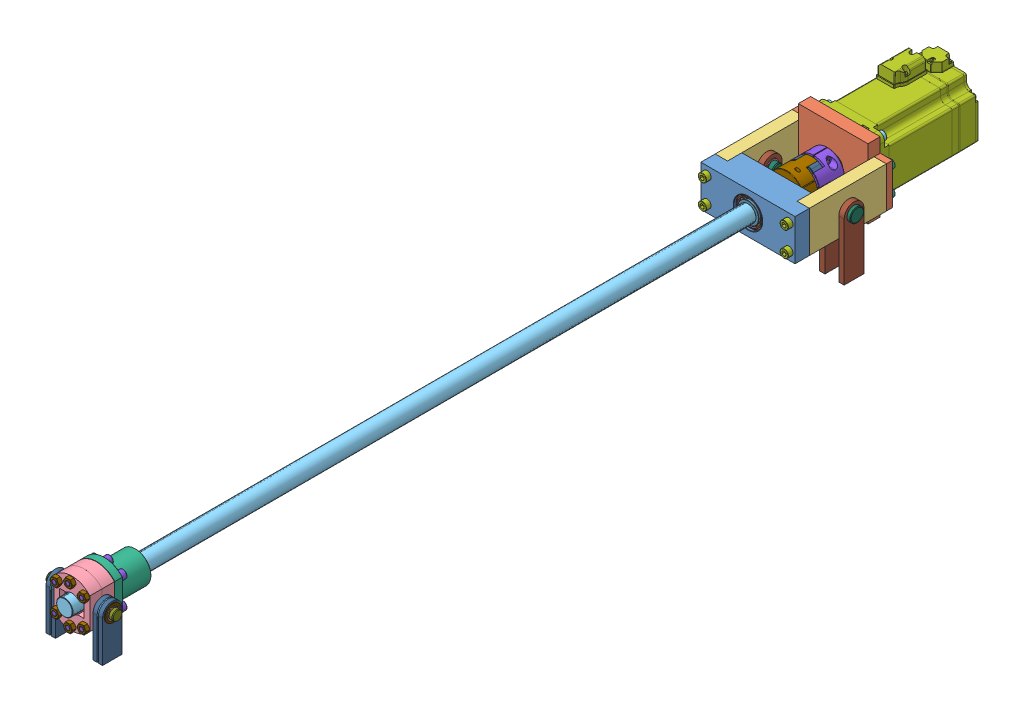
SolidWorks assembly full_assembly, configuration Domyślna. Lengths in mm.
Overall size (138 126.5 1076.27).
102 component instances, 29 part files, 150 mates.
Components (placement in the parent):
- kołyska gora-1: kołyska gora [Domyślna] at (65 70 76.5) x (-1 0 0) z (0 0 -1) size (115 50 35)
- kolyska doł-1: kolyska doł [Domyślna] at (65 70 -42.5) size (115 85 15)
- kolyska bok-2: kolyska bok [Domyślna] at (22.5 45 -35) x (0 1 0) z (0 0 1) size (50 15 94)
- kolyska bok-1: kolyska bok [Domyślna] at (122.5 45 -35) x (0 1 0) z (0 0 1) size (50 15 94)
- nakladka-1: nakladka [Domyślna] at (65 70 902.2231) x (0 -1 0) z (0 0 -1) size (58 44 15)
- nakladka-2: nakladka [Domyślna] at (65 70 872.2231) x (0 1 0) z (0 0 1) size (58 44 15)
- sruba-1: sruba [Domyślna] at (65 70 911.25) x (0 -1 0) z (0 0 -1) size (20 20 900)
- kolnierz-1: kolnierz [Domyślna] at (65 70 862.2231) x (0 1 0) z (0 0 1) size (58 44 48)
- serwo hiwin-1: serwo hiwin [Domyślna] at (64.9998 69.9998 -39.5) x (1 0 0) z (0 1 0) size (80.01 162.52 96.51)
- sprzeglo ekl 19 12-2: sprzeglo ekl 19 12 [Domyślna] at (55.554 -10.7595 3.0501) x (-1 0 0) z (0 1 0) size (83.78 50.01 62.16)
  - EKL_Size20.STEP-1: EKL_Size20.STEP [Domyślna] at (-9.446 -23.7001 80.7595) size (83.78 50.01 62.16)
    - 3D_EKL_020_Nabe1.STEP-1: 3D_EKL_020_Nabe1.STEP [Domyślna] at origin size (83.78 31.01 42)
    - 3D_EKL_020_Nabe2.STEP-1: 3D_EKL_020_Nabe2.STEP [Domyślna] x (0.218377 0 -0.975864) z (0.975864 0 0.218377) size (51.25 31.01 42.01)
    - 3D_EKL_020_Stern.STEP-1: 3D_EKL_020_Stern.STEP [Domyślna] x (0.866025 0 0.5) z (-0.5 0 0.866025) size (39.47 12 42)
- SKF_30202-1: SKF_30202 [Default] at (65 70 64.5) x (0 0 1) z (0.198521 -0.980097 0) size (12.37 35 35)
  - SKF_30202_3-1: SKF_30202_3 [Default] x (1 0 0) z (0 0 -1) size (9.25 35 35)
  - SKF_30202_5-1: SKF_30202_5 [Default] x (1 0 0) z (0 -0.433884 -0.900969) size (8.32 5.94 4.84)
  - SKF_30202_5-2: SKF_30202_5 [Default] x (1 0 0) z (0 -0.781831 -0.62349) size (8.32 5.94 4.84)
  - SKF_30202_5-3: SKF_30202_5 [Default] x (1 0 0) z (0 -0.974928 -0.222521) size (8.32 5.94 4.84)
  - SKF_30202_5-4: SKF_30202_5 [Default] x (1 0 0) z (0 -0.974928 0.222521) size (8.32 5.94 4.84)
  - SKF_30202_5-5: SKF_30202_5 [Default] x (1 0 0) z (0 -0.781831 0.62349) size (8.32 5.94 4.84)
  - SKF_30202_5-6: SKF_30202_5 [Default] x (1 0 0) z (0 -0.433884 0.900969) size (8.32 5.94 4.84)
  - SKF_30202_5-7: SKF_30202_5 [Default] at origin size (8.32 5.94 4.84)
  - SKF_30202_5-8: SKF_30202_5 [Default] x (1 0 0) z (0 0.433884 0.900969) size (8.32 5.94 4.84)
  - SKF_30202_5-9: SKF_30202_5 [Default] x (1 0 0) z (0 0.781831 0.62349) size (8.32 5.94 4.84)
  - SKF_30202_5-10: SKF_30202_5 [Default] x (1 0 0) z (0 0.974928 0.222521) size (8.32 5.94 4.84)
  - SKF_30202_5-11: SKF_30202_5 [Default] x (1 0 0) z (0 0.974928 -0.222521) size (8.32 5.94 4.84)
  - SKF_30202_5-12: SKF_30202_5 [Default] x (1 0 0) z (0 0.781831 -0.62349) size (8.32 5.94 4.84)
  - SKF_30202_5-13: SKF_30202_5 [Default] x (1 0 0) z (0 0.433884 -0.900969) size (8.32 5.94 4.84)
  - SKF_30202_5-14: SKF_30202_5 [Default] x (1 0 0) z (0 0 -1) size (8.32 5.94 4.84)
  - SKF_30202_20-1: SKF_30202_20 [Default] x (1 0 0) z (0 0 -1) size (11.52 31.49 31.49)
  - SKF_30202_22-1: SKF_30202_22 [Default] x (1 0 0) z (0 0 -1) size (11 25.6 25.6)
- SKF_30202-2: SKF_30202 [Default] at (65 70 53.5) x (0 0 -1) z (-0.411353 -0.911476 0) size (12.37 35 35)
  - SKF_30202_3-1: SKF_30202_3 [Default] x (1 0 0) z (0 0 -1) size (9.25 35 35)
  - SKF_30202_5-1: SKF_30202_5 [Default] x (1 0 0) z (0 -0.433884 -0.900969) size (8.32 5.94 4.84)
  - SKF_30202_5-2: SKF_30202_5 [Default] x (1 0 0) z (0 -0.781831 -0.62349) size (8.32 5.94 4.84)
  - SKF_30202_5-3: SKF_30202_5 [Default] x (1 0 0) z (0 -0.974928 -0.222521) size (8.32 5.94 4.84)
  - SKF_30202_5-4: SKF_30202_5 [Default] x (1 0 0) z (0 -0.974928 0.222521) size (8.32 5.94 4.84)
  - SKF_30202_5-5: SKF_30202_5 [Default] x (1 0 0) z (0 -0.781831 0.62349) size (8.32 5.94 4.84)
  - SKF_30202_5-6: SKF_30202_5 [Default] x (1 0 0) z (0 -0.433884 0.900969) size (8.32 5.94 4.84)
  - SKF_30202_5-7: SKF_30202_5 [Default] at origin size (8.32 5.94 4.84)
  - SKF_30202_5-8: SKF_30202_5 [Default] x (1 0 0) z (0 0.433884 0.900969) size (8.32 5.94 4.84)
  - SKF_30202_5-9: SKF_30202_5 [Default] x (1 0 0) z (0 0.781831 0.62349) size (8.32 5.94 4.84)
  - SKF_30202_5-10: SKF_30202_5 [Default] x (1 0 0) z (0 0.974928 0.222521) size (8.32 5.94 4.84)
  - SKF_30202_5-11: SKF_30202_5 [Default] x (1 0 0) z (0 0.974928 -0.222521) size (8.32 5.94 4.84)
  - SKF_30202_5-12: SKF_30202_5 [Default] x (1 0 0) z (0 0.781831 -0.62349) size (8.32 5.94 4.84)
  - SKF_30202_5-13: SKF_30202_5 [Default] x (1 0 0) z (0 0.433884 -0.900969) size (8.32 5.94 4.84)
  - SKF_30202_5-14: SKF_30202_5 [Default] x (1 0 0) z (0 0 -1) size (8.32 5.94 4.84)
  - SKF_30202_20-1: SKF_30202_20 [Default] x (1 0 0) z (0 0 -1) size (11.52 31.49 31.49)
  - SKF_30202_22-1: SKF_30202_22 [Default] x (1 0 0) z (0 0 -1) size (11 25.6 25.6)
- sworzen 12x30-1: sworzen 12x30 [Domyślna] at (-4 70 12) x (1 0 0) z (0 -1 0) size (41 17 17)
- sworzen 12x30-2: sworzen 12x30 [Domyślna] at (134 70 12) x (-1 0 0) z (0 1 0) size (41 17 17)
- sworzen krótki-3: sworzen krótki [Domyślna] at (76 70 887.2231) size (30 17 17)
- sworzen krótki-4: sworzen krótki [Domyślna] at (53.9821 70 887.2231) x (-1 0 0) z (0 0 1) size (30 17 17)
- tuleja slizgowa-1: tuleja slizgowa [Domyślna] at (6.5 70 12) x (1 0 0) z (0 0.085752 0.996317) size (7 20 20)
- tuleja slizgowa-2: tuleja slizgowa [Domyślna] at (106.5 70 12) size (7 20 20)
- tuleja slizgowa-3: tuleja slizgowa [Domyślna] at (123.5 70 12) x (-1 0 0) z (0 -0.010008 -0.99995) size (7 20 20)
- tuleja slizgowa-4: tuleja slizgowa [Domyślna] at (23.5 70 12) x (-1 0 0) z (0 0 -1) size (7 20 20)
- tuleja krotka-11: tuleja krotka [Domyślna] at (87 70 887.2231) size (6 20 20)
- tuleja krotka-12: tuleja krotka [Domyślna] at (29.4821 70 887.2231) x (1 0 0) z (0 0.988972 -0.148103) size (6 20 20)
- tuleja krotka-13: tuleja krotka [Domyślna] at (43 70 887.2231) x (-1 0 0) z (0 0 -1) size (6 20 20)
- tuleja krotka-14: tuleja krotka [Domyślna] at (100.5 70 887.2231) x (-1 0 0) z (0 0 -1) size (6 20 20)
- podkladka slizgowa-3: podkladka slizgowa [Domyślna] at (35.5 70 887.2231) x (0 0 -1) z (1 0 0) size (24 24 1.5)
- podkladka slizgowa-4: podkladka slizgowa [Domyślna] at (93 70 887.2231) x (0 0 -1) z (1 0 0) size (24 24 1.5)
- kn 02 din 981-1: kn 02 din 981 [Default] at (65 70 40.75) x (0 0 -1) z (-0.707107 0.707107 0) size (5 22 22)
- podkladka lozysko-1: podkladka lozysko [Default] at (65 70 40.75) x (0 -1 0) z (0 0 1) size (28 27.86 1)
- seger-1: seger [Default] at (99 70 12) x (0 0 -1) z (1 0 0) size (14.2 16.59 1)
- seger-2: seger [Default] at (30 70 12) x (0 0 -1) z (1 0 0) size (14.2 16.59 1)
- seger-6: seger [Default] at (28.4821 70 887.2231) x (0 1 0) z (1 0 0) size (14.2 16.59 1)
- seger-7: seger [Default] at (100.5 70 887.2231) x (0 1 0) z (1 0 0) size (14.2 16.59 1)
- m6 16mm-1: m6 16mm [Default] at (96.8198 38.1798 -50.5) x (0.495459 -0.868632 0) z (0 0 -1) size (10 10 22)
- m6 16mm-2: m6 16mm [Default] at (33.1798 38.1798 -50.5) x (-0.495459 0.868632 0) z (0 0 -1) size (10 10 22)
- m6 16mm-3: m6 16mm [Default] at (33.1798 101.8198 -50.5) x (-1 0 0) z (0 0 -1) size (10 10 22)
- m6 16mm-4: m6 16mm [Default] at (96.8198 101.8198 -50.5) x (-0.999986 0.005236 0) z (0 0 -1) size (10 10 22)
- m6 20mm-1: m6 20mm [Default] at (115 85 -42.5) x (-1 0 0) z (0 0 -1) size (10 10 26)
- m6 20mm-2: m6 20mm [Default] at (115 55 -42.5) x (-1 0 0) z (0 0 -1) size (10 10 26)
- m6 20mm-3: m6 20mm [Default] at (15 85 -42.5) x (-1 0 0) z (0 0 -1) size (10 10 26)
- m6 20mm-4: m6 20mm [Default] at (15 55 -42.5) x (-1 0 0) z (0 0 -1) size (10 10 26)
- m6 30mm-1: m6 30mm [Default] at (115 55 76.5) size (10 10 36)
- m6 30mm-2: m6 30mm [Default] at (15 55 76.5) size (10 10 36)
- m6 30mm-3: m6 30mm [Default] at (115 85 76.5) size (10 10 36)
- m6 30mm-4: m6 30mm [Default] at (15 85 76.5) size (10 10 36)
- m6 45mm-1: m6 45mm [Default] at (81.617 86.617 862.2231) x (-0.923728 -0.383049 0) z (0 0 -1) size (10 10 51)
- m6 45mm-2: m6 45mm [Default] at (65 93.5 862.2231) x (-0.923728 -0.383049 0) z (0 0 -1) size (10 10 51)
- m6 45mm-3: m6 45mm [Default] at (81.617 53.383 862.2231) x (-0.923728 -0.383049 0) z (0 0 -1) size (10 10 51)
- m6 45mm-4: m6 45mm [Default] at (48.383 86.617 862.2231) x (-0.923728 -0.383049 0) z (0 0 -1) size (10 10 51)
- m6 45mm-5: m6 45mm [Default] at (65 46.5 862.2231) x (-0.923728 -0.383049 0) z (0 0 -1) size (10 10 51)
- m6 45mm-6: m6 45mm [Default] at (48.383 53.383 862.2231) x (-0.923728 -0.383049 0) z (0 0 -1) size (10 10 51)
- nakretka m6-1: nakretka m6 [Default] at (48.383 53.383 902.2231) size (11.55 10 5.26)
- nakretka m6-2: nakretka m6 [Default] at (65 46.5 902.2231) size (11.55 10 5.26)
- nakretka m6-3: nakretka m6 [Default] at (81.617 53.383 902.2231) size (11.55 10 5.26)
- nakretka m6-4: nakretka m6 [Default] at (65 93.5 902.2231) size (11.55 10 5.26)
- nakretka m6-5: nakretka m6 [Default] at (48.383 86.617 902.2231) size (11.55 10 5.26)
- nakretka m6-6: nakretka m6 [Default] at (81.617 86.617 902.2231) size (11.55 10 5.26)
- ciegno-9: ciegno [Domyślna] at (42 70 875.2231) x (0 -1 0) z (-1 0 0) size (62 24 5)
- ciegno-10: ciegno [Domyślna] at (88 70 899.2231) x (0 -1 0) z (1 0 0) size (62 24 5)
- ciegno-11: ciegno [Domyślna] at (30.4821 70 899.2231) x (0 -1 0) z (1 0 0) size (62 24 5)
- ciegno-12: ciegno [Domyślna] at (99.5 70 875.2231) x (0 -1 0) z (-1 0 0) size (62 24 5)
- ucho-1: ucho [Domyślna] at (0 70 12) x (0 0 -1) z (1 0 0) size (24 82 6.5)
- ucho-2: ucho [Domyślna] at (23.5 70 12) x (0 0 -1) z (1 0 0) size (24 82 6.5)
- ucho-3: ucho [Domyślna] at (100 70 12) x (0 0 -1) z (1 0 0) size (24 82 6.5)
- ucho-4: ucho [Domyślna] at (123.5 70 12) x (0 0 -1) z (1 0 0) size (24 82 6.5)
Mates (geometry in assembly coordinates):
- Wspólnie3: coincident anti-aligned: plane of SKF_30202-1/SKF_30202_22-1 through (72.9388 71.608 76.25) normal (0 0 1); plane of sruba-1 through (65 70 76.25) normal (0 0 -1)
- Wspólnie21: coincident aligned: plane of ucho-1 through (6.5 0 12) normal (0 -1 0); plane of ucho-2 through (30 0 12) normal (0 -1 0)
- Wspólnie22: coincident aligned: plane of ucho-3 through (106.5 0 12) normal (0 -1 0); plane of ucho-4 through (130 0 12) normal (0 -1 0)
- Wspólnie23: coincident aligned: plane of ucho-2 through (30 0 12) normal (0 -1 0); plane of ucho-3 through (106.5 0 12) normal (0 -1 0)
- Wspólnie24: coincident anti-aligned: plane of ucho-1 through (0 70 12) normal (-1 0 0); plane of sworzen 12x30-1 through (0 70 20.5) normal (1 0 0)
- Wspólnie25: coincident anti-aligned: plane of ucho-4 through (130 70 12) normal (1 0 0); plane of sworzen 12x30-2 through (130 70 20.5) normal (-1 0 0)
- Koncentryczne22: concentric anti-aligned: cylinder of sworzen 12x30-1 through (37 70 12) axis (1 0 0) radius 6; cylinder of tuleja slizgowa-1 through (6.5 70 12) axis (-1 0 0) radius 6
- Wspólnie27: coincident anti-aligned: plane of ucho-1 through (6.5 70 12) normal (1 0 0); plane of tuleja slizgowa-1 through (6.5 75.9779 11.4855) normal (-1 0 0)
- Koncentryczne23: concentric aligned: cylinder of sworzen 12x30-2 through (93 70 12) axis (-1 0 0) radius 6; cylinder of tuleja slizgowa-2 through (106.5 70 12) axis (-1 0 0) radius 6
- Wspólnie29: coincident anti-aligned: plane of ucho-3 through (106.5 70 12) normal (1 0 0); plane of tuleja slizgowa-2 through (106.5 76 12) normal (-1 0 0)
- Koncentryczne24: concentric anti-aligned: cylinder of sworzen 12x30-2 through (93 70 12) axis (-1 0 0) radius 6; cylinder of tuleja slizgowa-3 through (123.5 70 12) axis (1 0 0) radius 6
- Wspólnie30: coincident anti-aligned: plane of ucho-4 through (123.5 70 12) normal (-1 0 0); plane of tuleja slizgowa-3 through (123.5 75.9997 11.94) normal (1 0 0)
- Koncentryczne25: concentric aligned: cylinder of sworzen 12x30-1 through (37 70 12) axis (1 0 0) radius 6; cylinder of tuleja slizgowa-4 through (23.5 70 12) axis (1 0 0) radius 7
- Wspólnie32: coincident anti-aligned: plane of ucho-2 through (23.5 70 12) normal (-1 0 0); plane of tuleja slizgowa-4 through (23.5 76 12) normal (1 0 0)
- Wspólnie47: coincident anti-aligned: plane of sworzen 12x30-1 through (30 70 12) normal (1 0 0); plane of seger-2 through (30 68.7412 12) normal (-1 0 0)
- Koncentryczne36: concentric anti-aligned: cylinder of sworzen 12x30-1 through (30 70 12) axis (1 0 0) radius 5.75; cylinder of seger-2 through (30 70 12) axis (-1 0 0) radius 5.75
- Wspólnie49: coincident anti-aligned: plane of sworzen 12x30-2 through (100 70 12) normal (-1 0 0); plane of seger-1 through (100 68.7412 12) normal (1 0 0)
- Koncentryczne37: concentric aligned: cylinder of sworzen 12x30-2 through (100 70 12) axis (-1 0 0) radius 5.75; cylinder of seger-1 through (99 70 12) axis (-1 0 0) radius 5.75
- Równolegle3: parallel anti-aligned: plane of sruba-1 through (65 70 911.25) normal (-1 0 0)
- Koncentryczne65: concentric anti-aligned: cylinder of kołyska gora-1 through (65 70 41.5) axis (0 0 1) radius 14; cylinder of SKF_30202-2/SKF_30202_22-1 through (65 70 41.75) axis (0 0 -1) radius 7.5
- Koncentryczne66: concentric aligned: cylinder of kołyska gora-1 through (65 70 41.5) axis (0 0 1) radius 14; cylinder of SKF_30202-1/SKF_30202_22-1 through (65 70 76.25) axis (0 0 1) radius 7.5
- Wspólnie79: coincident anti-aligned: plane of kołyska gora-1 through (65 70 64.5) normal (0 0 1); plane of SKF_30202-1/SKF_30202_3-1 through (81.5636 73.355 64.5) normal (0 0 -1)
- Wspólnie80: coincident anti-aligned: plane of kołyska gora-1 through (65 70 53.5) normal (0 0 -1); plane of SKF_30202-2/SKF_30202_3-1 through (49.5961 76.9519 53.5) normal (0 0 1)
- Koncentryczne67: concentric anti-aligned: cylinder of kołyska gora-1 through (65 70 41.5) axis (0 0 1) radius 14; cylinder of sruba-1 through (65 70 76.25) axis (0 0 -1) radius 7.5
- Prostopadle3: perpendicular: plane of kołyska gora-1 through (122.5 95 41.5) normal (0 1 0); plane of sworzen 12x30-1 through (-4 70 12) normal (0 0 1)
- Prostopadle4: perpendicular: plane of kołyska gora-1 through (122.5 95 41.5) normal (0 1 0); plane of sworzen 12x30-2 through (134 70 12) normal (0 0 1)
- Koncentryczne68: concentric aligned: cylinder of kołyska gora-1 through (15 85 41.5) axis (0 0 1) radius 3.25; cylinder of m6 30mm-4 through (15 85 62.2706) axis (0 0 1) radius 3
- Wspólnie81: coincident anti-aligned: plane of kołyska gora-1 through (65 70 76.5) normal (0 0 1); plane of m6 30mm-4 through (12.5 85 76.5) normal (0 0 -1)
- Koncentryczne69: concentric aligned: cylinder of kołyska gora-1 through (15 55 41.5) axis (0 0 1) radius 3.25; cylinder of m6 30mm-2 through (15 55 62.2706) axis (0 0 1) radius 3
- Wspólnie82: coincident anti-aligned: plane of kołyska gora-1 through (65 70 76.5) normal (0 0 1); plane of m6 30mm-2 through (12.5 55 76.5) normal (0 0 -1)
- Wspólnie83: coincident anti-aligned: plane of kołyska gora-1 through (65 70 76.5) normal (0 0 1); plane of m6 30mm-3 through (112.5 85 76.5) normal (0 0 -1)
- Wspólnie84: coincident anti-aligned: plane of kołyska gora-1 through (65 70 76.5) normal (0 0 1); plane of m6 30mm-1 through (112.5 55 76.5) normal (0 0 -1)
- Koncentryczne70: concentric aligned: cylinder of kołyska gora-1 through (115 85 41.5) axis (0 0 1) radius 3.25; cylinder of m6 30mm-3 through (115 85 62.2706) axis (0 0 1) radius 3
- Koncentryczne71: concentric aligned: cylinder of kołyska gora-1 through (115 55 41.5) axis (0 0 1) radius 3.25; cylinder of m6 30mm-1 through (115 55 62.2706) axis (0 0 1) radius 3
- Koncentryczne72: concentric aligned: cylinder of kolyska bok-1 through (122.5 70 12) axis (-1 0 0) radius 7; cylinder of ucho-3 through (106.5 70 12) axis (-1 0 0) radius 6
- Koncentryczne73: concentric aligned: cylinder of kolyska bok-1 through (122.5 70 12) axis (-1 0 0) radius 7; cylinder of ucho-4 through (130 70 12) axis (-1 0 0) radius 6
- Koncentryczne74: concentric aligned: cylinder of kolyska bok-1 through (122.5 70 12) axis (-1 0 0) radius 7; cylinder of sworzen 12x30-2 through (93 70 12) axis (-1 0 0) radius 6
- Wspólnie86: coincident anti-aligned: plane of kolyska bok-1 through (107.5 45 12) normal (-1 0 0); plane of tuleja slizgowa-2 through (107.5 80 12) normal (1 0 0)
- Wspólnie87: coincident anti-aligned: plane of kolyska bok-1 through (122.5 45 12) normal (1 0 0); plane of tuleja slizgowa-3 through (122.5 79.9995 11.8999) normal (-1 0 0)
- Koncentryczne75: concentric aligned: cylinder of kolyska bok-1 through (115 55 39) axis (0 0 1) radius 2.5; cylinder of kołyska gora-1 through (115 55 41.5) axis (0 0 1) radius 3.25
- Koncentryczne76: concentric aligned: cylinder of kolyska bok-1 through (115 85 39) axis (0 0 1) radius 2.5; cylinder of kołyska gora-1 through (115 85 41.5) axis (0 0 1) radius 3.25
- Wspólnie88: coincident anti-aligned: plane of kolyska bok-1 through (122.5 45 59) normal (0 0 1); plane of kołyska gora-1 through (65 70 59) normal (0 0 -1)
- Koncentryczne77: concentric aligned: cylinder of kolyska bok-2 through (22.5 70 12) axis (-1 0 0) radius 7; cylinder of ucho-1 through (6.5 70 12) axis (-1 0 0) radius 6
- Koncentryczne78: concentric aligned: cylinder of kolyska bok-2 through (22.5 70 12) axis (-1 0 0) radius 7; cylinder of ucho-2 through (30 70 12) axis (-1 0 0) radius 6
- Koncentryczne79: concentric anti-aligned: cylinder of kolyska bok-2 through (22.5 70 12) axis (-1 0 0) radius 7; cylinder of sworzen 12x30-1 through (37 70 12) axis (1 0 0) radius 6
- Wspólnie89: coincident anti-aligned: plane of kolyska bok-2 through (7.5 45 12) normal (-1 0 0); plane of tuleja slizgowa-1 through (7.5 79.9632 11.1425) normal (1 0 0)
- Wspólnie90: coincident anti-aligned: plane of kolyska bok-2 through (22.5 45 12) normal (1 0 0); plane of tuleja slizgowa-4 through (22.5 80 12) normal (-1 0 0)
- Koncentryczne80: concentric aligned: cylinder of kolyska doł-1 through (115 85 -27.5) axis (0 0 -1) radius 3.25; cylinder of m6 20mm-1 through (115 85 -33.2706) axis (0 0 -1) radius 3
- Wspólnie92: coincident anti-aligned: plane of kolyska doł-1 through (65 70 -42.5) normal (0 0 -1); plane of m6 20mm-1 through (117.5 85 -42.5) normal (0 0 1)
- Koncentryczne81: concentric aligned: cylinder of kolyska doł-1 through (115 55 -27.5) axis (0 0 -1) radius 3.25; cylinder of m6 20mm-2 through (115 55 -33.2706) axis (0 0 -1) radius 3
- Wspólnie93: coincident anti-aligned: plane of kolyska doł-1 through (65 70 -42.5) normal (0 0 -1); plane of m6 20mm-2 through (117.5 55 -42.5) normal (0 0 1)
- Koncentryczne82: concentric aligned: cylinder of kolyska doł-1 through (15 85 -27.5) axis (0 0 -1) radius 3.25; cylinder of m6 20mm-3 through (15 85 -33.2706) axis (0 0 -1) radius 3
- Wspólnie94: coincident anti-aligned: plane of kolyska doł-1 through (65 70 -42.5) normal (0 0 -1); plane of m6 20mm-3 through (17.5 85 -42.5) normal (0 0 1)
- Koncentryczne83: concentric aligned: cylinder of kolyska doł-1 through (15 55 -27.5) axis (0 0 -1) radius 3.25; cylinder of m6 20mm-4 through (15 55 -33.2706) axis (0 0 -1) radius 3
- Wspólnie95: coincident anti-aligned: plane of kolyska doł-1 through (65 70 -42.5) normal (0 0 -1); plane of m6 20mm-4 through (17.5 55 -42.5) normal (0 0 1)
- Koncentryczne86: concentric aligned: cylinder of kolyska doł-1 through (115 55 -27.5) axis (0 0 -1) radius 3.25; cylinder of kolyska bok-1 through (115 55 -15) axis (0 0 -1) radius 2.5
- Koncentryczne87: concentric aligned: cylinder of kolyska doł-1 through (115 85 -27.5) axis (0 0 -1) radius 3.25; cylinder of kolyska bok-1 through (115 85 -15) axis (0 0 -1) radius 2.5
- Wspólnie96: coincident anti-aligned: plane of kolyska doł-1 through (65 70 -35) normal (0 0 1); plane of kolyska bok-1 through (122.5 45 -35) normal (0 0 -1)
- Koncentryczne88: concentric aligned: cylinder of kolyska doł-1 through (15 55 -27.5) axis (0 0 -1) radius 3.25; cylinder of kolyska bok-2 through (15 55 -15) axis (0 0 -1) radius 2.5
- Koncentryczne89: concentric aligned: cylinder of kolyska doł-1 through (15 85 -27.5) axis (0 0 -1) radius 3.25; cylinder of kolyska bok-2 through (15 85 -15) axis (0 0 -1) radius 2.5
- Wspólnie97: coincident anti-aligned: plane of kolyska doł-1 through (65 70 -35) normal (0 0 1); plane of kolyska bok-2 through (22.5 45 -35) normal (0 0 -1)
- Koncentryczne100: concentric anti-aligned: cylinder of kolyska doł-1 through (65 70 -27.5) axis (0 0 -1) radius 12; cylinder of serwo hiwin-1 through (64.9998 69.9998 -29.15) axis (0 0 1) radius 9.5
- Wspólnie110: coincident anti-aligned: plane of kolyska doł-1 through (65 70 -42.5) normal (0 0 -1); plane of serwo hiwin-1 through (64.9998 69.9998 -42.5) normal (0 0 1)
- Koncentryczne101: concentric aligned: cylinder of m6 16mm-4 through (96.8198 101.8198 -43.2706) axis (0 0 -1) radius 3; cylinder of serwo hiwin-1 through (96.8198 101.8198 -49.15) axis (0 0 -1) radius 3.3
- Wspólnie111: coincident anti-aligned: plane of m6 16mm-4 through (99.3198 101.8067 -50.5) normal (0 0 1); plane of serwo hiwin-1 through (100.8998 105.8998 -50.5) normal (0 0 -1)
- Koncentryczne102: concentric aligned: cylinder of m6 16mm-1 through (96.8198 38.1798 -43.2706) axis (0 0 -1) radius 3; cylinder of serwo hiwin-1 through (96.8198 38.1798 -49.15) axis (0 0 -1) radius 3.3
- Wspólnie112: coincident anti-aligned: plane of m6 16mm-1 through (95.5812 40.3514 -50.5) normal (0 0 1); plane of serwo hiwin-1 through (100.8998 34.0998 -50.5) normal (0 0 -1)
- Koncentryczne103: concentric aligned: cylinder of m6 16mm-2 through (33.1798 38.1798 -43.2706) axis (0 0 -1) radius 3; cylinder of serwo hiwin-1 through (33.1798 38.1798 -49.15) axis (0 0 -1) radius 3.3
- Wspólnie113: coincident anti-aligned: plane of m6 16mm-2 through (34.4185 36.0082 -50.5) normal (0 0 1); plane of serwo hiwin-1 through (29.0998 34.0998 -50.5) normal (0 0 -1)
- Koncentryczne104: concentric aligned: cylinder of m6 16mm-3 through (33.1798 101.8198 -43.2706) axis (0 0 -1) radius 3; cylinder of serwo hiwin-1 through (33.1798 101.8198 -49.15) axis (0 0 -1) radius 3.3
- Wspólnie114: coincident anti-aligned: plane of m6 16mm-3 through (35.6798 101.8198 -50.5) normal (0 0 1); plane of serwo hiwin-1 through (29.0998 105.8998 -50.5) normal (0 0 -1)
- Koncentryczne105: concentric anti-aligned: cylinder of serwo hiwin-1 through (64.9998 69.9998 -29.15) axis (0 0 1) radius 9.5; cylinder of sprzeglo ekl 19 12-2/EKL_Size20.STEP-1/3D_EKL_020_Nabe1.STEP-1 through (65 70 -3.65) axis (0 0 -1) radius 9.5
- Koncentryczne106: concentric anti-aligned: cylinder of sruba-1 through (65 70 29.25) axis (0 0 -1) radius 6; cylinder of sprzeglo ekl 19 12-2/EKL_Size20.STEP-1/3D_EKL_020_Nabe2.STEP-1 through (65 70 12.25) axis (0 0 1) radius 6
- Równolegle21: parallel aligned: plane of kolyska bok-2 through (7.5 45 12) normal (-1 0 0); plane of sprzeglo ekl 19 12-2/EKL_Size20.STEP-1/3D_EKL_020_Nabe1.STEP-1 through (65.5 91 -3.65) normal (-1 0 0)
- Wspólnie123: coincident anti-aligned: plane of sruba-1 through (65 70 29.25) normal (0 0 -1); plane of sprzeglo ekl 19 12-2/EKL_Size20.STEP-1/3D_EKL_020_Nabe2.STEP-1 through (65 70 29.25) normal (0 0 1)
- Koncentryczne112: concentric aligned: cylinder of kolyska doł-1 through (96.8198 101.8198 -32.5) axis (0 0 -1) radius 2.5; cylinder of m6 16mm-4 through (96.8198 101.8198 -43.2706) axis (0 0 -1) radius 3
- Wspólnie132: coincident anti-aligned: plane of ucho-1 through (6.5 0 12) normal (0 -1 0)
- Wspólnie133: coincident anti-aligned: plane of ucho-1 through (6.5 70 0) normal (0 0 -1)
- Wspólnie134: coincident anti-aligned: plane of ucho-1 through (0 70 12) normal (-1 0 0)
- Równolegle23: parallel aligned: plane of serwo hiwin-1 through (64.9899 29.9899 -55.81) normal (0 -1 0); plane of ucho-1 through (6.5 0 12) normal (0 -1 0)
- Wspólnie135: coincident anti-aligned: plane of nakladka-1 through (65 70 887.2231) normal (0 0 -1); plane of nakladka-2 through (65 70 887.2231) normal (0 0 1)
- Koncentryczne113: concentric anti-aligned: cylinder of nakladka-1 through (81.617 53.383 887.2231) axis (0 0 1) radius 3.3; cylinder of nakladka-2 through (81.617 53.383 887.2231) axis (0 0 -1) radius 3.3
- Koncentryczne114: concentric anti-aligned: cylinder of nakladka-1 through (48.383 86.617 887.2231) axis (0 0 1) radius 3.3; cylinder of nakladka-2 through (48.383 86.617 887.2231) axis (0 0 -1) radius 3.3
- Koncentryczne118: concentric aligned: cylinder of nakladka-2 through (43 70 887.2231) axis (1 0 0) radius 6; cylinder of sworzen krótki-3 through (106 70 887.2231) axis (1 0 0) radius 6
- Wspólnie137: coincident anti-aligned: plane of nakladka-1 through (80 78.5 902.2231) normal (-1 0 0); plane of sworzen krótki-3 through (80 78.5 887.2231) normal (1 0 0)
- Koncentryczne119: concentric anti-aligned: cylinder of nakladka-2 through (43 70 887.2231) axis (1 0 0) radius 6; cylinder of sworzen krótki-4 through (23.9821 70 887.2231) axis (-1 0 0) radius 6
- Wspólnie138: coincident anti-aligned: plane of nakladka-1 through (49.9821 78.5 902.2231) normal (1 0 0); plane of sworzen krótki-4 through (49.9821 61.5 887.2231) normal (-1 0 0)
- Koncentryczne120: concentric aligned: cylinder of sworzen krótki-4 through (29.4821 70 887.2231) axis (-1 0 0) radius 5.75; cylinder of seger-6 through (28.4821 70 887.2231) axis (-1 0 0) radius 5.75
- Wspólnie140: coincident anti-aligned: plane of sworzen krótki-4 through (29.4821 70 887.2231) normal (-1 0 0); plane of seger-6 through (29.4821 70 885.9642) normal (1 0 0)
- Koncentryczne121: concentric anti-aligned: cylinder of sworzen krótki-3 through (100.5 70 887.2231) axis (1 0 0) radius 5.75; cylinder of seger-7 through (100.5 70 887.2231) axis (-1 0 0) radius 5.75
- Wspólnie141: coincident anti-aligned: plane of sworzen krótki-3 through (100.5 70 887.2231) normal (1 0 0); plane of seger-7 through (100.5 70 885.9642) normal (-1 0 0)
- Koncentryczne122: concentric aligned: cylinder of sworzen krótki-4 through (23.9821 70 887.2231) axis (-1 0 0) radius 6; cylinder of tuleja krotka-12 through (29.4821 70 887.2231) axis (-1 0 0) radius 6
- Koncentryczne124: concentric anti-aligned: cylinder of sworzen krótki-4 through (23.9821 70 887.2231) axis (-1 0 0) radius 6; cylinder of tuleja krotka-13 through (43 70 887.2231) axis (1 0 0) radius 6
- Wspólnie142: coincident anti-aligned: plane of nakladka-1 through (43 88.8944 887.2231) normal (-1 0 0); plane of tuleja krotka-13 through (43 76 887.2231) normal (1 0 0)
- Koncentryczne125: concentric anti-aligned: cylinder of sworzen krótki-3 through (106 70 887.2231) axis (1 0 0) radius 6; cylinder of tuleja krotka-11 through (87 70 887.2231) axis (-1 0 0) radius 6
- Wspólnie143: coincident anti-aligned: plane of nakladka-1 through (87 88.8944 887.2231) normal (1 0 0); plane of tuleja krotka-11 through (87 76 887.2231) normal (-1 0 0)
- Koncentryczne126: concentric aligned: cylinder of tuleja krotka-13 through (43 70 887.2231) axis (1 0 0) radius 7; cylinder of ciegno-9 through (37 70 887.2231) axis (1 0 0) radius 7
- Wspólnie144: coincident anti-aligned: plane of tuleja krotka-13 through (42 80 887.2231) normal (-1 0 0); plane of ciegno-9 through (42 70 887.2231) normal (1 0 0)
- Wspólnie145: coincident anti-aligned: plane of tuleja krotka-11 through (88 80 887.2231) normal (1 0 0); plane of ciegno-10 through (88 70 887.2231) normal (-1 0 0)
- Koncentryczne127: concentric aligned: cylinder of tuleja krotka-11 through (87 70 887.2231) axis (-1 0 0) radius 7; cylinder of ciegno-10 through (93 70 887.2231) axis (-1 0 0) radius 7
- Koncentryczne128: concentric aligned: cylinder of sworzen krótki-4 through (23.9821 70 887.2231) axis (-1 0 0) radius 6; cylinder of podkladka slizgowa-3 through (37 70 887.2231) axis (-1 0 0) radius 6
- Wspólnie146: coincident anti-aligned: plane of podkladka slizgowa-3 through (37 70 887.2231) normal (1 0 0); plane of ciegno-9 through (37 70 887.2231) normal (-1 0 0)
- Wspólnie147: coincident anti-aligned: plane of podkladka slizgowa-4 through (93 70 887.2231) normal (-1 0 0); plane of ciegno-10 through (93 70 887.2231) normal (1 0 0)
- Koncentryczne129: concentric anti-aligned: cylinder of sworzen krótki-3 through (106 70 887.2231) axis (1 0 0) radius 6; cylinder of podkladka slizgowa-4 through (94.5 70 887.2231) axis (-1 0 0) radius 6
- Wspólnie148: coincident anti-aligned: plane of tuleja krotka-14 through (94.5 76 887.2231) normal (-1 0 0); plane of podkladka slizgowa-4 through (94.5 70 887.2231) normal (1 0 0)
- Koncentryczne130: concentric aligned: cylinder of sworzen krótki-3 through (106 70 887.2231) axis (1 0 0) radius 6; cylinder of tuleja krotka-14 through (100.5 70 887.2231) axis (1 0 0) radius 6
- Wspólnie149: coincident anti-aligned: plane of seger-6 through (29.4821 70 885.9642) normal (1 0 0); plane of tuleja krotka-12 through (29.4821 69.1114 881.2892) normal (-1 0 0)
- Koncentryczne131: concentric aligned: cylinder of tuleja krotka-12 through (29.4821 70 887.2231) axis (-1 0 0) radius 7; cylinder of ciegno-11 through (35.4821 70 887.2231) axis (-1 0 0) radius 7
- Wspólnie150: coincident anti-aligned: plane of tuleja krotka-12 through (30.4821 68.519 877.3334) normal (1 0 0); plane of ciegno-11 through (30.4821 70 887.2231) normal (-1 0 0)
- Wspólnie151: coincident anti-aligned: plane of tuleja krotka-14 through (99.5 80 887.2231) normal (-1 0 0); plane of ciegno-12 through (99.5 70 887.2231) normal (1 0 0)
- Koncentryczne132: concentric aligned: cylinder of tuleja krotka-14 through (100.5 70 887.2231) axis (1 0 0) radius 7; cylinder of ciegno-12 through (94.5 70 887.2231) axis (1 0 0) radius 7
- Koncentryczne133: concentric aligned: cylinder of podkladka lozysko-1 through (65 70 41.25) axis (0 0 -1) radius 7.5; cylinder of sruba-1 through (65 70 76.25) axis (0 0 -1) radius 7.5
- Wspólnie152: coincident anti-aligned: plane of sruba-1 through (59 70 49.25) normal (-1 0 0); plane of podkladka lozysko-1 through (59 70 41.25) normal (1 0 0)
- Wspólnie153: coincident anti-aligned: plane of SKF_30202-2/SKF_30202_22-1 through (57.617 73.332 41.75) normal (0 0 -1); plane of podkladka lozysko-1 through (65 70 41.75) normal (0 0 1)
- Wspólnie154: coincident anti-aligned: plane of kn 02 din 981-1 through (61.1109 66.1109 40.75) normal (0 0 1); plane of podkladka lozysko-1 through (65 70 40.75) normal (0 0 -1)
- Wspólnie156: coincident anti-aligned: plane of kn 02 din 981-1 through (52.5 72 38.25) normal (0 -1 0); plane of podkladka lozysko-1 through (57.8191 72 41.25) normal (0 1 0)
- Koncentryczne146: concentric anti-aligned: cylinder of sruba-1 through (65 70 76.25) axis (0 0 -1) radius 7.5; cylinder of kn 02 din 981-1 through (65 70 38.25) axis (0 0 1) radius 6.9587
- Koncentryczne147: concentric aligned: cylinder of nakladka-2 through (81.617 86.617 887.2231) axis (0 0 -1) radius 3.3; cylinder of kolnierz-1 through (81.617 86.617 872.2231) axis (0 0 -1) radius 3.3
- Koncentryczne148: concentric aligned: cylinder of nakladka-2 through (48.383 53.383 887.2231) axis (0 0 -1) radius 3.3; cylinder of kolnierz-1 through (48.383 53.383 872.2231) axis (0 0 -1) radius 3.3
- Koncentryczne149: concentric anti-aligned: cylinder of sruba-1 through (65 70 11.25) axis (0 0 1) radius 10; cylinder of kolnierz-1 through (65 70 872.2231) axis (0 0 -1) radius 10
- Koncentryczne150: concentric aligned: cylinder of m6 45mm-6 through (48.383 53.383 871.9524) axis (0 0 -1) radius 3; cylinder of kolnierz-1 through (48.383 53.383 872.2231) axis (0 0 -1) radius 3.3
- Koncentryczne151: concentric aligned: cylinder of m6 45mm-5 through (65 46.5 871.9524) axis (0 0 -1) radius 3; cylinder of kolnierz-1 through (65 46.5 872.2231) axis (0 0 -1) radius 3.3
- Koncentryczne152: concentric aligned: cylinder of m6 45mm-3 through (81.617 53.383 871.9524) axis (0 0 -1) radius 3; cylinder of kolnierz-1 through (81.617 53.383 872.2231) axis (0 0 -1) radius 3.3
- Koncentryczne153: concentric aligned: cylinder of m6 45mm-4 through (48.383 86.617 871.9524) axis (0 0 -1) radius 3; cylinder of kolnierz-1 through (48.383 86.617 872.2231) axis (0 0 -1) radius 3.3
- Koncentryczne154: concentric aligned: cylinder of m6 45mm-2 through (65 93.5 871.9524) axis (0 0 -1) radius 3; cylinder of kolnierz-1 through (65 93.5 872.2231) axis (0 0 -1) radius 3.3
- Koncentryczne155: concentric aligned: cylinder of m6 45mm-1 through (81.617 86.617 871.9524) axis (0 0 -1) radius 3; cylinder of kolnierz-1 through (81.617 86.617 872.2231) axis (0 0 -1) radius 3.3
- Wspólnie169: coincident anti-aligned: plane of m6 45mm-1 through (83.9263 87.5746 862.2231) normal (0 0 1); plane of kolnierz-1 through (65 70 862.2231) normal (0 0 -1)
- Wspólnie170: coincident anti-aligned: plane of m6 45mm-2 through (67.3093 94.4576 862.2231) normal (0 0 1); plane of kolnierz-1 through (65 70 862.2231) normal (0 0 -1)
- Wspólnie171: coincident anti-aligned: plane of m6 45mm-4 through (50.6923 87.5746 862.2231) normal (0 0 1); plane of kolnierz-1 through (65 70 862.2231) normal (0 0 -1)
- Wspólnie172: coincident anti-aligned: plane of m6 45mm-6 through (50.6923 54.3406 862.2231) normal (0 0 1); plane of kolnierz-1 through (65 70 862.2231) normal (0 0 -1)
- Wspólnie173: coincident anti-aligned: plane of m6 45mm-5 through (67.3093 47.4576 862.2231) normal (0 0 1); plane of kolnierz-1 through (65 70 862.2231) normal (0 0 -1)
- Wspólnie174: coincident anti-aligned: plane of m6 45mm-3 through (83.9263 54.3406 862.2231) normal (0 0 1); plane of kolnierz-1 through (65 70 862.2231) normal (0 0 -1)
- Wspólnie175: coincident anti-aligned: plane of nakladka-2 through (65 70 872.2231) normal (0 0 -1); plane of kolnierz-1 through (65 70 872.2231) normal (0 0 1)
- Równolegle37: parallel aligned: plane of kołyska gora-1 through (122.5 45 41.5) normal (1 0 0); plane of kolnierz-1 through (87 70 872.2231) normal (1 0 0)
- Koncentryczne156: concentric aligned: cylinder of m6 45mm-6 through (48.383 53.383 894.9524) axis (0 0 -1) radius 3; cylinder of nakretka m6-1 through (48.383 53.383 904.7231) axis (0 0 -1) radius 2.4588
- Koncentryczne157: concentric aligned: cylinder of m6 45mm-5 through (65 46.5 894.9524) axis (0 0 -1) radius 3; cylinder of nakretka m6-2 through (65 46.5 904.7231) axis (0 0 -1) radius 2.4588
- Koncentryczne158: concentric aligned: cylinder of m6 45mm-3 through (81.617 53.383 894.9524) axis (0 0 -1) radius 3; cylinder of nakretka m6-3 through (81.617 53.383 904.7231) axis (0 0 -1) radius 2.4588
- Koncentryczne159: concentric aligned: cylinder of m6 45mm-1 through (81.617 86.617 894.9524) axis (0 0 -1) radius 3; cylinder of nakretka m6-6 through (81.617 86.617 904.7231) axis (0 0 -1) radius 2.4588
- Koncentryczne160: concentric aligned: cylinder of m6 45mm-4 through (48.383 86.617 894.9524) axis (0 0 -1) radius 3; cylinder of nakretka m6-5 through (48.383 86.617 904.7231) axis (0 0 -1) radius 2.4588
- Koncentryczne161: concentric aligned: cylinder of m6 45mm-2 through (65 93.5 894.9524) axis (0 0 -1) radius 3; cylinder of nakretka m6-4 through (65 93.5 904.7231) axis (0 0 -1) radius 2.4588
- Wspólnie176: coincident anti-aligned: plane of nakladka-1 through (65 70 902.2231) normal (0 0 1); plane of nakretka m6-1 through (48.383 53.383 902.2231) normal (0 0 -1)
- Wspólnie177: coincident anti-aligned: plane of nakladka-1 through (65 70 902.2231) normal (0 0 1); plane of nakretka m6-2 through (65 46.5 902.2231) normal (0 0 -1)
- Wspólnie178: coincident anti-aligned: plane of nakladka-1 through (65 70 902.2231) normal (0 0 1); plane of nakretka m6-3 through (81.617 53.383 902.2231) normal (0 0 -1)
- Wspólnie179: coincident anti-aligned: plane of nakladka-1 through (65 70 902.2231) normal (0 0 1); plane of nakretka m6-6 through (81.617 86.617 902.2231) normal (0 0 -1)
- Wspólnie180: coincident anti-aligned: plane of nakladka-1 through (65 70 902.2231) normal (0 0 1); plane of nakretka m6-4 through (65 93.5 902.2231) normal (0 0 -1)
- Wspólnie182: coincident anti-aligned: plane of nakladka-1 through (65 70 902.2231) normal (0 0 1); plane of nakretka m6-5 through (48.383 86.617 902.2231) normal (0 0 -1)
- Równolegle46: parallel aligned: plane of nakretka m6-3 through (81.617 48.383 902.2231) normal (0 -1 0); plane of ciegno-12 through (94.5 20 875.2231) normal (0 -1 0)
- Równolegle47: parallel aligned: plane of nakretka m6-3 through (81.617 48.383 902.2231) normal (0 -1 0); plane of ciegno-10 through (93 20 899.2231) normal (0 -1 0)
- Równolegle48: parallel aligned: plane of nakretka m6-3 through (81.617 48.383 902.2231) normal (0 -1 0); plane of ciegno-9 through (37 20 875.2231) normal (0 -1 0)
- Równolegle49: parallel aligned: plane of nakretka m6-3 through (81.617 48.383 902.2231) normal (0 -1 0); plane of ciegno-11 through (35.4821 20 899.2231) normal (0 -1 0)
